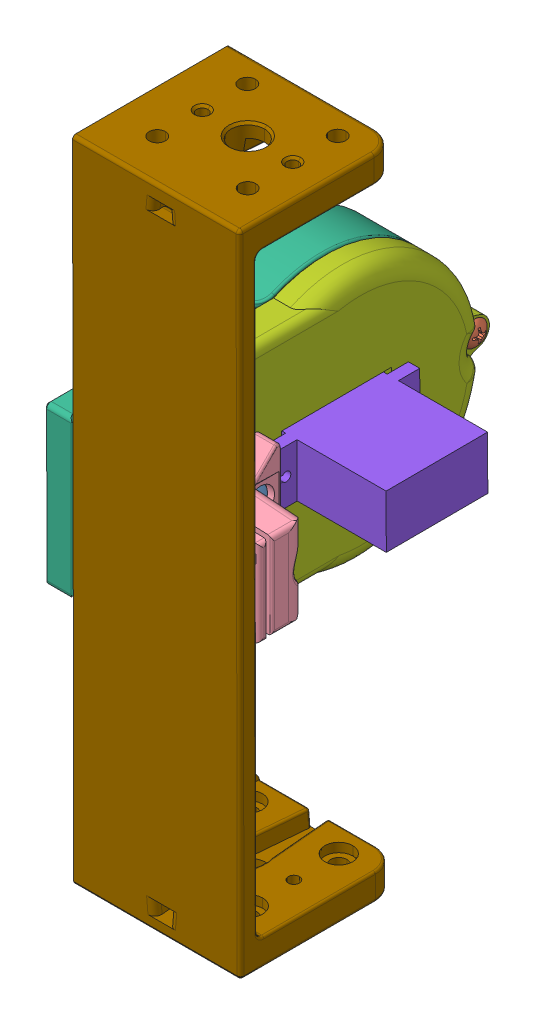
SolidWorks assembly ASSY-Joint-Linear-Module-STEP, configuration Predeterminado. Lengths in mm.
Overall size (43.63 144.29 82.4).
16 component instances, 9 part files, 0 mates.
Components (placement in the parent):
- ASSY-Joint-Linear-Module-STEP.stp-1: ASSY-Joint-Linear-Module-STEP.stp [Predeterminado] at origin size (43.63 144.29 82.4)
  - ASSY_Actuator_HORZ.1.stp-1: ASSY_Actuator_HORZ.1.stp [Predeterminado] at (382.0792 -227.6108 -34.2415) x (0 -0.999994 -0.003544) z (0 0.003544 -0.999994) size (144 43.63 81.89)
    - GearBox.stp-1: GearBox.stp [Predeterminado] at (-574.5919 160.5006 84.0735) x (0.999998 0 0.001772) z (-0.001772 -0.001772 0.999997) size (56.14 43.49 81.71)
      - 90380A107_PHILLIPS_THREAD-FORM.STEP.stp-1: 90380A107_PHILLIPS_THREAD-FORM.STEP.stp [Predeterminado] at (346.3364 221.37 -117.9007) x (0 -0.999998 0.001772) z (-0.001772 -0.001772 -0.999997) size (33.24 32.56 75.85)
        - 90380A107_PHILLIPS_THREAD-FO_1.prt.2.stp-1: 90380A107_PHILLIPS_THREAD-FO_1.prt.2.stp [Predeterminado] at (137.873 173.0323 100.5502) x (-0.707107 -0.002506 -0.707102) z (0.707102 0.001038 -0.70711) size (5.56 5.56 9.92)
        - 90380A107_PHILLIPS_THREAD-FO_1.prt.2.stp-2: 90380A107_PHILLIPS_THREAD-FO_1.prt.2.stp [Predeterminado] at (123.592 172.9802 88.2513) x (0 0 -1) z (1 0 0) size (5.56 5.56 9.92)
        - 90380A107_PHILLIPS_THREAD-FO_1.prt.3.1.stp-1: 90380A107_PHILLIPS_THREAD-FO_1.prt.3.1.stp [Predeterminado] at (116.342 172.9802 32.264) x (0 0 -1) z (1 0 0) size (5.56 5.56 11.48)
        - 90380A107_PHILLIPS_THREAD-FO_1.prt.3.1.stp-2: 90380A107_PHILLIPS_THREAD-FO_1.prt.3.1.stp [Predeterminado] at (116.342 186.5512 98.6245) x (0 0 -1) z (1 0 0) size (5.56 5.56 11.48)
        - 90380A107_PHILLIPS_THREAD-FO_1.prt.3.1.stp-3: 90380A107_PHILLIPS_THREAD-FO_1.prt.3.1.stp [Predeterminado] at (116.842 159.5512 98.6724) x (0 0 -1) z (1 0 0) size (5.56 5.56 11.48)
      - gearv_V2.stp-1: gearv_V2.stp [Predeterminado] at (705.0597 486.0918 153.4703) x (0 -0.999998 0.001772) z (0.083636 -0.001766 -0.996495) size (11.8 50.89 50.89)
      - tensioner.stp-1: tensioner.stp [Predeterminado] at (346.6524 221.3689 -118.515) x (0 -0.999998 0.001772) z (-0.005316 -0.001772 -0.999984) size (25 19.11 23.01)
      - horn.2.stp-1: horn.2.stp [Predeterminado] at (346.0836 -1.5219 -270.3531) x (0 0.999998 -0.001772) z (0.001772 0.001772 0.999997) size (4.3 7 22.78)
      - Base_Gearbox.1.stp-1: Base_Gearbox.1.stp [Predeterminado] at (574.442 -149.0182 -84.8276) x (0.999998 -0.000003 -0.001772) z (0.001772 0.001772 0.999997) size (56 20.9 81.58)
      - Cover-gearbox-actuator.stp-1: Cover-gearbox-actuator.stp [Predeterminado] at (574.442 -158.5682 -84.8106) x (0.999998 -0.000003 -0.001772) z (0.001772 0.001772 0.999997) size (56 8.2 77.69)
      - servo_SG90.1.1.stp-1: servo_SG90.1.1.stp [Predeterminado] at (261.6232 60.3135 2.8306) x (0 0.999998 -0.001772) z (-0.999998 0.000003 0.001772) size (33.75 31.9 11.8)
    - rack.1.stp-1: rack.1.stp [Predeterminado] at (-53.0344 0 -5.041) size (144 37 35.22)
